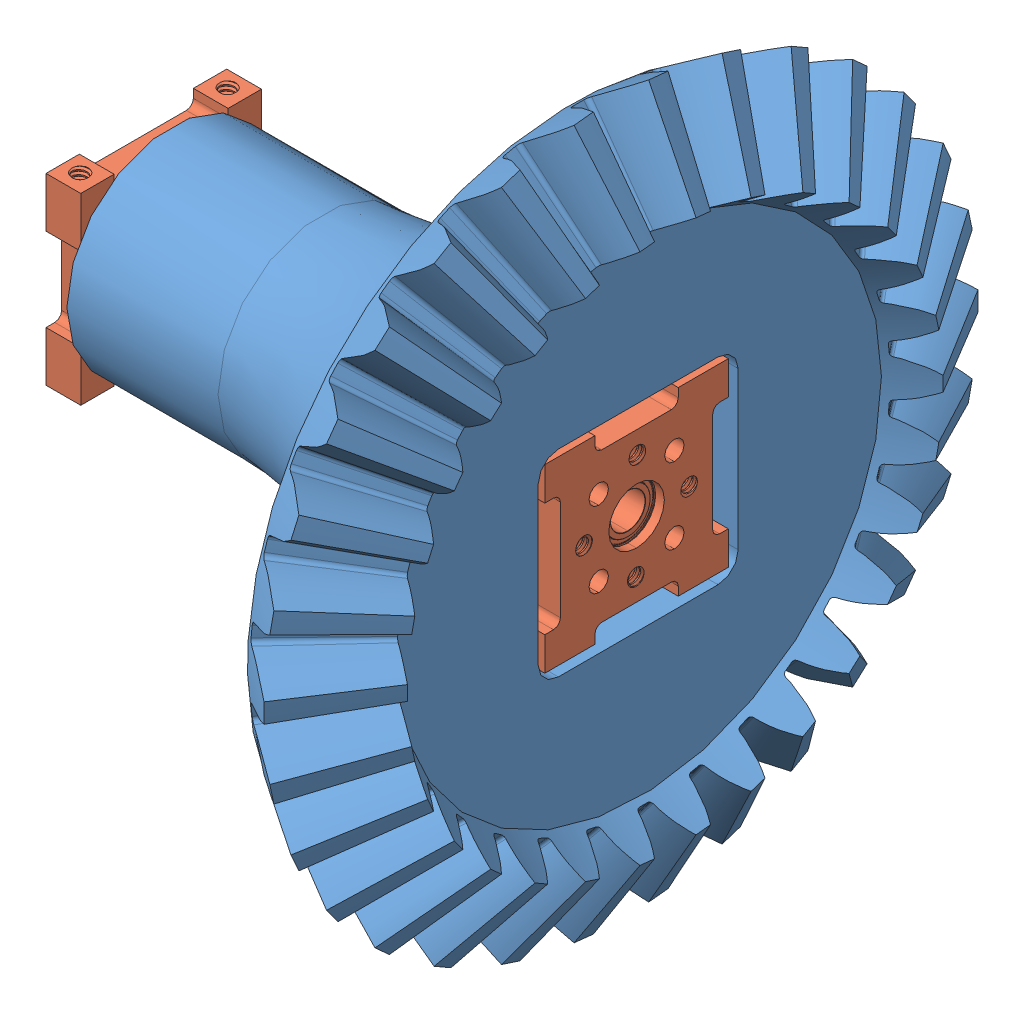
SolidWorks assembly ARMUS-101-400, configuration Défaut. Lengths in mm.
Overall size (99.55 130.43 130.79).
3 component instances, 2 part files, 8 mates.
Components (placement in the parent):
- ARMUS-REV2-401-1: ARMUS-REV2-401 [Default] at origin size (93.2 130.43 130.79)
- Bore Side Tapped Pillow Block 1.25-1: Bore Side Tapped Pillow Block 1.25 [Default] at (-58.9626 7.6184 28.3917) x (0 -1 0) z (0 0 -1) size (33.54 6.35 33.02)
- Bore Side Tapped Pillow Block 1.25-2: Bore Side Tapped Pillow Block 1.25 [Default] at (26.0822 -28.3917 7.6184) x (0 0 -1) z (0 1 0) size (33.54 6.35 33.02)
Mates (geometry in assembly coordinates):
- Concentric294: concentric anti-aligned: cylinder of ARMUS-REV2-401-1 through (128.2701 0 0) axis (-1 0 0) radius 6.35; cylinder of Bore Side Tapped Pillow Block 1.25-2 through (5.5295 0 0) axis (1 0 0) radius 3.175
- Concentric296: concentric anti-aligned: cylinder of ARMUS-REV2-401-1 through (5.5168 -6.9148 -6.9148) axis (1 0 0) radius 1.25; cylinder of Bore Side Tapped Pillow Block 1.25-2 through (5.5168 -6.9148 -6.9148) axis (-1 0 0) radius 1.778
- Concentric297: concentric anti-aligned: cylinder of ARMUS-REV2-401-1 through (5.5168 6.9148 -6.9148) axis (1 0 0) radius 1.25; cylinder of Bore Side Tapped Pillow Block 1.25-2 through (5.5168 6.9148 -6.9148) axis (-1 0 0) radius 1.778
- Coincident59: coincident anti-aligned: plane of ARMUS-REV2-401-1 through (5.5168 0 0) normal (1 0 0); plane of Bore Side Tapped Pillow Block 1.25-2 through (5.5168 0 0) normal (-1 0 0)
- Coincident60: coordinate: point of ARMUS-REV2-401-1
- Concentric299: concentric anti-aligned: cylinder of ARMUS-REV2-401-1 through (5.5168 -6.9148 -6.9148) axis (1 0 0) radius 1.25; cylinder of Bore Side Tapped Pillow Block 1.25-1 through (-79.5281 -6.9148 -6.9148) axis (-1 0 0) radius 1.778
- Coincident61: coincident anti-aligned: plane of ARMUS-REV2-401-1 through (-73.1781 -65.2174 -19.05) normal (-1 0 0); plane of Bore Side Tapped Pillow Block 1.25-1 through (-73.1781 0 0) normal (1 0 0)
- Concentric301: concentric anti-aligned: cylinder of ARMUS-REV2-401-1 through (5.5168 6.9148 6.9148) axis (1 0 0) radius 1.25; cylinder of Bore Side Tapped Pillow Block 1.25-1 through (-79.5281 6.9148 6.9148) axis (-1 0 0) radius 1.778
